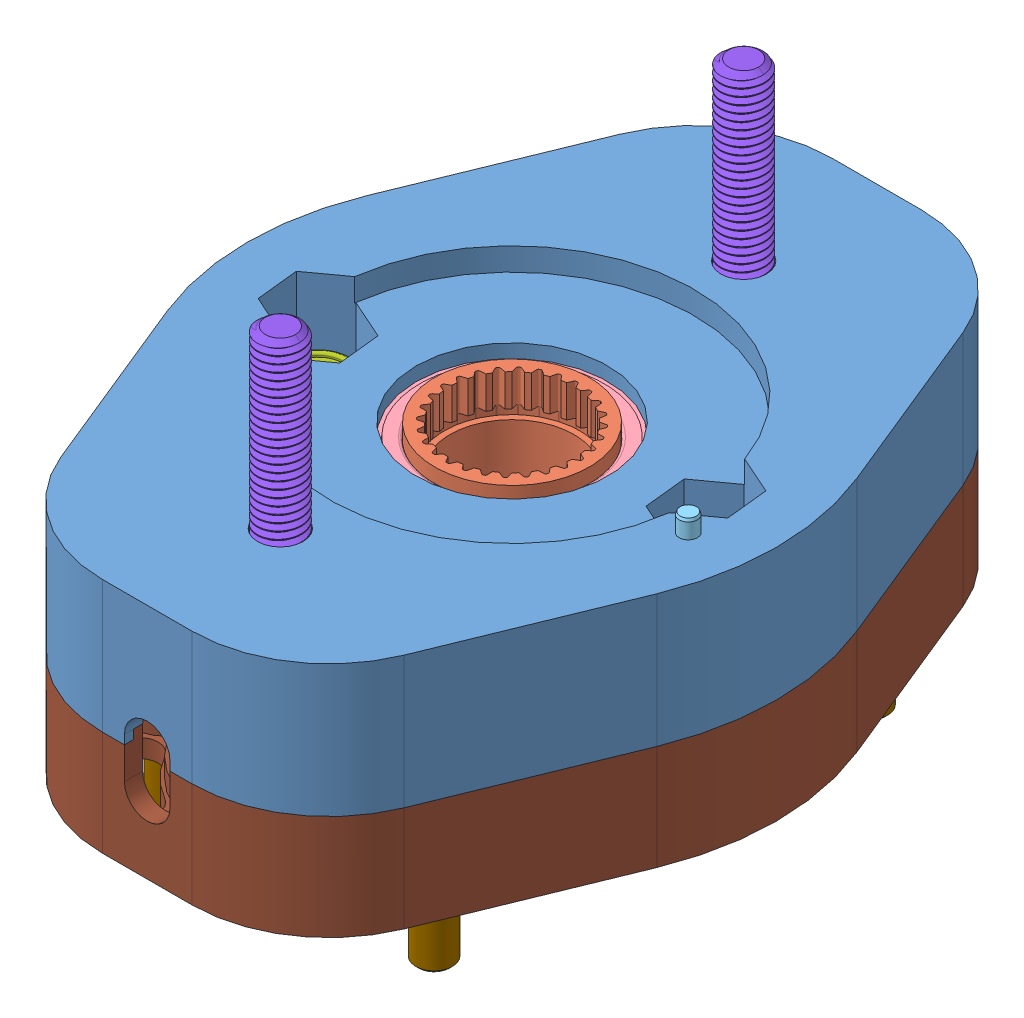
SolidWorks assembly 217-3141-RS775-STEP, configuration Default. Lengths in mm.
Overall size (58 53.22 83.15).
22 component instances, 12 part files, 43 mates.
Components (placement in the parent):
- 217-3141-001 Rev1-1: 217-3141-001 Rev1 [Default] at (-61.459 -0.0001 22.3173) x (0 0 1) z (-1 0 0) size (80 14.5 58)
- 217-3141-007 Rev1_30T 32DP-1: 217-3141-007 Rev1_30T 32DP [Default] at (-61.459 -7.06 22.3173) x (0 -1 0) z (-0.999183 0 0.040426) size (22.38 25.55 25.47)
- 217-3141-006 Rev1_30T 32DP-1: 217-3141-006 Rev1_30T 32DP [Default] at (-60.6253 -8.45 -1.5569) x (-0.491042 0 -0.871136) z (0 -1 0) size (25.47 25.55 10)
- 217-3141-006 Rev1_30T 32DP-2: 217-3141-006 Rev1_30T 32DP [Default] at (-60.6253 -8.45 46.1914) x (-0.70455 0 0.709654) z (0 -1 0) size (25.47 25.55 10)
- 217-2741-1: 217-2741 [Default] at (-61.459 2.75 22.3173) x (0 -1 0) z (-0.999445 0 -0.033298) size (5 26 26)
- 217-2741-2: 217-2741 [Default] at (-61.459 -13.25 22.3173) x (0 -1 0) z (-0.537831 0 0.843053) size (5 26 26)
- PINL-M020-006-S-1: PINL-M020-006-S [Default] at (-38.7145 5.7499 25.7357) x (0 1 0) z (-0.890225 0 0.455522) size (6 2 2)
- SSS1032-0188-ZB-1: SSS1032-0188-ZB [Default] at (-62.5919 -10.325 -5.0458) x (0.78519 -0.43311 -0.442597) z (0.491042 0 0.871136) size (4.91 4.91 5.06)
- SSS1032-0188-ZB-2: SSS1032-0188-ZB [Default] at (-63.447 -10.325 49.0336) x (0.387287 -0.837954 0.384502) z (0.70455 0 -0.709654) size (4.91 4.91 5.06)
- NUT-832-NYLOCK-1: NUT-832-NYLOCK [Default] at (-42.215 -4.7501 20.2947) x (-0.913545 0 -0.406737) z (0.406737 0 -0.913545) size (10.2 4.9 8.12)
- NUT-832-NYLOCK-2: NUT-832-NYLOCK [Default] at (-80.703 -4.7501 24.3399) x (0.912648 0 0.408747) z (-0.408747 0 0.912648) size (10.2 4.9 8.12)
- 91251A346_91251A346-1: 91251A346_91251A346 [Default] at (-61.459 25.9749 47.7173) x (1 0 0) z (0 1 0) size (7.92 7.92 27.28)
- 91251A346_91251A346-2: 91251A346_91251A346 [Default] at (-61.459 25.9749 -3.0827) x (1 0 0) z (0 1 0) size (7.92 7.92 27.28)
- SSA_SSAM4-0010ZC-1: SSA_SSAM4-0010ZC [Default] at (-46.1253 -17.25 -1.5569) size (7 14 7)
- SSA_SSA0832-0750ZC-1: SSA_SSA0832-0750ZC [Default] at (-80.703 -19.25 24.3399) x (-0.091926 0 -0.995766) z (-0.995766 0 0.091926) size (6.73 23.11 6.73)
- SSA_SSA0832-0750ZC-2: SSA_SSA0832-0750ZC [Default] at (-42.215 -19.25 20.2947) x (-0.18632 0 -0.982489) z (-0.982489 0 0.18632) size (6.73 23.11 6.73)
- SSA_SSAM4-0010ZC-2: SSA_SSAM4-0010ZC [Default] at (-75.1253 -17.25 46.1914) x (0.677756 0 0.735287) z (-0.735287 0 0.677756) size (7 14 7)
- SSA_SSAM4-0010ZC-3: SSA_SSAM4-0010ZC [Default] at (-46.1253 -17.25 46.1914) x (0.994338 0 -0.106265) z (0.106265 0 0.994338) size (7 14 7)
- SSA_SSAM4-0010ZC-4: SSA_SSAM4-0010ZC [Default] at (-75.1253 -17.25 -1.5569) x (0.537906 0 -0.843005) z (0.843005 0 0.537906) size (7 14 7)
- 217-3141-004 Rev1-1: 217-3141-004 Rev1 [Default] at (-61.459 -13 22.3173) x (0 0 1) z (0 1 0) size (80 58 12.5)
- 217-2625-013 Rev1-1: 217-2625-013 Rev1 [Default] at (-60.6253 -9.6 46.1914) x (1 0 0) z (0 1 0) size (8 7.93 7.5)
- 217-2625-013 Rev1-2: 217-2625-013 Rev1 [Default] at (-60.6253 -9.6 -1.5569) x (1 0 0) z (0 1 0) size (8 7.93 7.5)
Mates (geometry in assembly coordinates):
- Concentric1: concentric anti-aligned: cylinder of 217-3141-007 Rev1_30T 32DP-1 through (-61.459 -25.0196 22.3173) axis (0 -1 0) radius 8.4955; cylinder of 217-2741-1 through (-61.459 2.75 22.3173) axis (0 1 0) radius 8.5
- Concentric2: concentric anti-aligned: cylinder of 217-3141-007 Rev1_30T 32DP-1 through (-61.459 -25.0196 22.3173) axis (0 -1 0) radius 8.4955; cylinder of 217-2741-2 through (-61.459 -13.25 22.3173) axis (0 1 0) radius 8.5
- Concentric3: concentric anti-aligned: cylinder of 217-2741-2 through (-61.459 -13.25 22.3173) axis (0 1 0) radius 13; cylinder of 217-3141-004 Rev1-1 through (-61.459 -14.75 22.3173) axis (0 -1 0) radius 13
- Coincident1: coincident anti-aligned: plane of 217-2741-2 through (-54.2931 -18.25 26.8888) normal (0 -1 0); plane of 217-3141-004 Rev1-1 through (-61.459 -18.25 22.3173) normal (0 1 0)
- Concentric4: concentric anti-aligned: cylinder of 217-3141-001 Rev1-1 through (-61.459 136.6291 -3.0827) axis (0 -1 0) radius 2.5; cylinder of 91251A346_91251A346-2 through (-61.459 128.8031 -3.0827) axis (0 1 0) radius 3.9624
- Concentric5: concentric anti-aligned: cylinder of 217-3141-001 Rev1-1 through (-61.459 136.6291 47.7173) axis (0 -1 0) radius 2.5; cylinder of 91251A346_91251A346-1 through (-61.459 128.8031 47.7173) axis (0 1 0) radius 3.9624
- Concentric6: concentric anti-aligned: circle of 217-3141-001 Rev1-1; circle of 217-2741-2
- Concentric7: concentric anti-aligned: cylinder of SSA_SSA0832-0750ZC-2 through (-42.215 -23.314 20.2947) axis (0 1 0) radius 3.3655; cylinder of 217-3141-004 Rev1-1 through (-42.215 -6.75 20.2947) axis (0 -1 0) radius 2.1526
- Concentric8: concentric anti-aligned: circle of SSA_SSA0832-0750ZC-1; cylinder of 217-3141-004 Rev1-1 through (-80.703 -6.75 24.3399) axis (0 -1 0) radius 2.1526
- Coincident2: coincident anti-aligned: plane of SSA_SSA0832-0750ZC-2 through (-42.215 -19.25 20.2947) normal (0 1 0); plane of 217-3141-004 Rev1-1 through (-61.459 -19.25 22.3173) normal (0 -1 0)
- Coincident3: coincident anti-aligned: plane of SSA_SSA0832-0750ZC-1 through (-80.703 -19.25 24.3399) normal (0 1 0); plane of 217-3141-004 Rev1-1 through (-61.459 -19.25 22.3173) normal (0 -1 0)
- Coincident4: coincident anti-aligned: plane of 217-3141-006 Rev1_30T 32DP-2 through (-60.6253 28.0787 46.1914) normal (0 -1 0); plane of 217-2625-013 Rev1-1 through (-60.6253 28.0787 46.1914) normal (0 1 0)
- Concentric9: concentric anti-aligned: cylinder of 217-3141-006 Rev1_30T 32DP-2 through (-60.6253 20.4787 46.1914) axis (0 1 0) radius 4.005; cylinder of 217-2625-013 Rev1-1 through (-60.6253 28.0787 46.1914) axis (0 -1 0) radius 2.51
- Coincident5: coincident anti-aligned: plane of 217-3141-006 Rev1_30T 32DP-1 through (-60.6253 -5.85 -1.5569) normal (0 -1 0); plane of 217-2625-013 Rev1-2 through (-60.6253 -5.85 -1.5569) normal (0 1 0)
- Concentric10: concentric anti-aligned: cylinder of 217-3141-006 Rev1_30T 32DP-1 through (-60.6253 -13.45 -1.5569) axis (0 1 0) radius 4.005; cylinder of 217-2625-013 Rev1-2 through (-60.6253 -5.85 -1.5569) axis (0 -1 0) radius 4
- Coincident6: coincident anti-aligned: plane of SSA_SSAM4-0010ZC-3 through (-46.1253 -17.25 46.1914) normal (0 -1 0); plane of 217-3141-004 Rev1-1 through (-61.459 -17.25 22.3173) normal (0 1 0)
- Concentric11: concentric aligned: cylinder of SSA_SSAM4-0010ZC-3 through (-46.1253 -27.25 46.1914) axis (0 1 0) radius 2; cylinder of 217-3141-004 Rev1-1 through (-46.1253 -19.25 46.1914) axis (0 1 0) radius 2.1
- Coincident7: coincident anti-aligned: plane of SSA_SSAM4-0010ZC-2 through (-75.1253 -17.25 46.1914) normal (0 -1 0); plane of 217-3141-004 Rev1-1 through (-61.459 -17.25 22.3173) normal (0 1 0)
- Concentric12: concentric aligned: circle of SSA_SSAM4-0010ZC-2; circle of 217-3141-004 Rev1-1
- Coincident8: coincident anti-aligned: plane of SSA_SSAM4-0010ZC-1 through (-46.1253 -17.25 -1.5569) normal (0 -1 0); plane of 217-3141-004 Rev1-1 through (-61.459 -17.25 22.3173) normal (0 1 0)
- Coincident9: coincident anti-aligned: plane of SSA_SSAM4-0010ZC-4 through (-75.1253 -17.25 -1.5569) normal (0 -1 0); plane of 217-3141-004 Rev1-1 through (-61.459 -17.25 22.3173) normal (0 1 0)
- Concentric13: concentric aligned: circle of SSA_SSAM4-0010ZC-1; cylinder of 217-3141-004 Rev1-1 through (-46.1253 -14.25 -1.5569) axis (0 -1 0) radius 3.75
- Concentric14: concentric aligned: circle of SSA_SSAM4-0010ZC-4; cylinder of 217-3141-004 Rev1-1 through (-75.1253 -14.25 -1.5569) axis (0 -1 0) radius 3.75
- Concentric15: concentric anti-aligned: cylinder of 217-3141-001 Rev1-1 through (-38.7145 132.6291 25.7357) axis (0 1 0) radius 1; cylinder of PINL-M020-006-S-1 through (-38.7145 138.6291 25.7357) axis (0 -1 0) radius 1.0001
- Coincident10: coincident anti-aligned: plane of 217-3141-001 Rev1-1 through (-38.7145 132.6291 25.7357) normal (0 1 0); plane of PINL-M020-006-S-1 through (-38.7145 132.6291 25.7357) normal (0 -1 0)
- Coincident11: coincident anti-aligned: plane of 217-3141-007 Rev1_30T 32DP-1 through (-61.0952 -13.25 31.3099) normal (0 -1 0); plane of 217-2741-2 through (-54.2931 -13.25 26.8888) normal (0 1 0)
- Coincident12: coincident anti-aligned: plane of 217-3141-007 Rev1_30T 32DP-1 through (-61.1156 -2.25 30.8058) normal (0 1 0); plane of 217-2741-1 through (-61.742 -2.25 30.8126) normal (0 -1 0)
- Coincident13: coincident anti-aligned: plane of 217-3141-001 Rev1-1 through (-61.459 133.6291 47.7173) normal (0 -1 0); plane of 91251A346_91251A346-1 through (-61.459 133.6291 47.7173) normal (0 1 0)
- Coincident14: coincident anti-aligned: plane of 217-3141-001 Rev1-1 through (-61.459 133.6291 -3.0827) normal (0 -1 0); plane of 91251A346_91251A346-2 through (-61.459 133.6291 -3.0827) normal (0 1 0)
- Coincident15: coincident anti-aligned: plane of 217-3141-001 Rev1-1 through (-61.459 125.1291 22.3173) normal (0 1 0); plane of NUT-832-NYLOCK-2 through (-80.2234 125.1291 29.0016) normal (0 -1 0)
- Coincident16: coincident anti-aligned: plane of 217-3141-001 Rev1-1 through (-61.459 125.1291 22.3173) normal (0 1 0); plane of NUT-832-NYLOCK-1 through (-42.7049 125.1291 15.634) normal (0 -1 0)
- Concentric16: concentric aligned: circle of 217-3141-001 Rev1-1; cylinder of NUT-832-NYLOCK-2 through (-80.703 125.1291 24.3399) axis (0 1 0) radius 1.6955
- Parallel1: parallel anti-aligned: plane of 217-3141-001 Rev1-1 through (-37.9164 110.4205 22.2085) normal (-0.994522 0 0.104528); plane of NUT-832-NYLOCK-1 through (-37.9339 128.7867 22.2008) normal (0.994522 0 -0.104528)
- Concentric17: concentric anti-aligned: circle of 217-3141-001 Rev1-1; circle of NUT-832-NYLOCK-1
- Concentric18: concentric anti-aligned: cylinder of 217-3141-006 Rev1_30T 32DP-2 through (-60.6253 20.4787 46.1914) axis (0 1 0) radius 8.4; cylinder of 217-3141-004 Rev1-1 through (-60.6253 -6.75 46.1914) axis (0 -1 0) radius 8.65
- Concentric19: concentric anti-aligned: cylinder of 217-3141-006 Rev1_30T 32DP-1 through (-60.6253 -13.45 -1.5569) axis (0 1 0) radius 8.4; cylinder of 217-3141-004 Rev1-1 through (-60.6253 -6.75 -1.5569) axis (0 -1 0) radius 8.65
- Concentric20: concentric anti-aligned: cylinder of 217-3141-006 Rev1_30T 32DP-2 through (-60.6253 23.6037 46.1914) axis (0.70455 0 -0.709654) radius 2.0193; circle of SSS1032-0188-ZB-2
- Tangent3: tangent: circle of 217-3141-006 Rev1_30T 32DP-2; plane of SSS1032-0188-ZB-2 through (-64.1222 22.984 48.3633) normal (0.70455 0 -0.709654)
- Concentric21: concentric anti-aligned: cylinder of 217-3141-006 Rev1_30T 32DP-1 through (-60.6253 -10.325 -1.5569) axis (0.491042 0 0.871136) radius 2.0193; circle of SSS1032-0188-ZB-1
- Tangent4: tangent: circle of 217-3141-006 Rev1_30T 32DP-1; plane of SSS1032-0188-ZB-1 through (-62.1635 -9.3016 -5.2872) normal (0.491042 0 0.871136)
- Coincident21: coincident aligned: plane of 217-3141-007 Rev1_30T 32DP-1 through (-61.0952 -3.45 31.3099) normal (0 1 0); plane of 217-3141-006 Rev1_30T 32DP-1 through (-60.6253 -3.45 -1.5569) normal (0 1 0)
- Coincident22: coincident aligned: plane of 217-3141-007 Rev1_30T 32DP-1 through (-61.0952 -3.45 31.3099) normal (0 1 0); plane of 217-3141-006 Rev1_30T 32DP-2 through (-60.6253 -3.45 46.1914) normal (0 1 0)
- Coincident23: coincident anti-aligned: plane of 217-3141-001 Rev1-1 through (-61.459 -7.75 22.3173) normal (0 -1 0); plane of 217-3141-004 Rev1-1 through (-56.5392 -7.75 -2.6827) normal (0 1 0)
